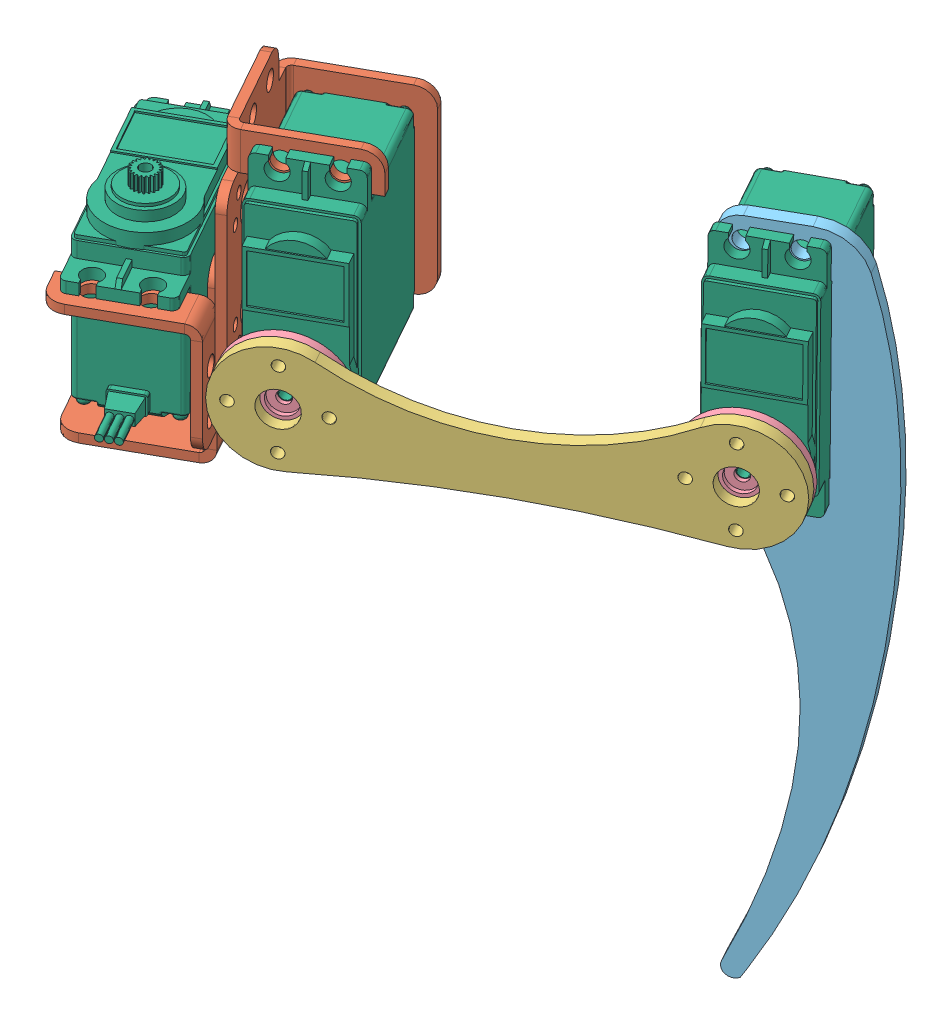
SolidWorks assembly left_leg, configuration Default. Lengths in mm.
Overall size (169.69 167.14 107.48).
10 component instances, 6 part files, 24 mates.
Components (placement in the parent):
- bearing-1: bearing [Default] at (77.3096 14.4854 59.4755) x (1 0 0) z (0 0 -1) size (9.5 4 9.5)
- coxa-1: coxa [Défaut] at (-9.8756 50.5854 -20.8316) x (0 -1 0) z (0.488008 0 0.872839) size (58 27 37.5)
- femur-1: femur [Default] at (-54.5147 84.2371 93.7229) x (-0.073248 -0.273612 -0.959047) z (0.868991 -0.489377 0.073248) size (45.33 66.4 77.86)
- metal horn-2: metal horn [Default] at (98.2503 39.7292 -104.3541) x (0.872817 -0.007119 -0.487995) z (-0.006214 -0.999975 0.003474) size (24 5 24)
- tibia-1: tibia [Default] at (-104.8708 38.6817 35.4135) x (-0.932842 0.242775 -0.266205) z (0.211271 -0.229899 -0.950006) size (45.21 146.32 43.03)
- coxa-2: coxa [Défaut] at (-2.1895 15.3354 -7.0844) x (-0.488008 0 -0.872839) z (0 1 0) size (58 27 37.5)
- servo-1: servo [Default] at (-23.955 42.3664 4.756) x (0.872839 0 -0.488008) z (0.488008 0 0.872839) size (19.81 42.14 58.23)
- servo-2: servo [Default] at (7.6485 50.8724 0.3396) x (0.872839 0 -0.488008) z (0 -1 0) size (19.81 42.14 58.23)
- servo-3: servo [Default] at (74.2287 50.408 -36.8856) x (0.872812 -0.007915 -0.487992) z (-0.006908 -0.999969 0.003863) size (19.81 42.14 58.23)
- metal horn-1: metal horn [Default] at (31.7415 40.2716 -67.1688) x (0.872817 -0.007119 -0.487995) z (-0.006214 -0.999975 0.003474) size (24 5 24)
Mates (geometry in assembly coordinates):
- Concentric1: concentric anti-aligned: cylinder of bracket-1 through (4.3143 40.8354 0.4498) axis (0.872839 0 -0.488008) radius 4; cylinder of bracket-2 through (0.8229 40.8354 2.4018) axis (-0.872839 0 0.488008) radius 4
- Concentric2: concentric anti-aligned: cylinder of bracket-1 through (0.8982 40.8354 -5.6601) axis (0.872839 0 -0.488008) radius 1.25; cylinder of bracket-2 through (-2.5931 40.8354 -3.7081) axis (-0.872839 0 0.488008) radius 1.25
- Coincident1: coincident anti-aligned: plane of bracket-1 through (-9.8756 30.0854 -20.8316) normal (-0.872839 0 0.488008); plane of bracket-2 through (-12.1936 15.3354 -24.9776) normal (0.872839 0 -0.488008)
- Coincident2: coincident anti-aligned: plane of bracket-2 through (-2.1895 48.3354 -7.0844) normal (0 1 0); plane of hs-422_sws-1 through (-6.6623 48.3354 -4.9124) normal (0 -1 0)
- Parallel2: parallel anti-aligned: plane of bracket-2 through (-13.9393 15.3354 -24.0016) normal (-0.872839 0 0.488008); plane of hs-422_sws-1 through (-6.6623 42.3664 -4.9124) normal (0.872839 0 -0.488008)
- Concentric7: concentric aligned: cylinder of hs-422_sws-1 through (-10.2885 54.0905 8.9007) axis (0 1 0) radius 1.27; cylinder of bracket-2 through (-10.2885 17.3354 8.9007) axis (0 1 0) radius 1.25
- Concentric16: concentric aligned: cylinder of ball bearing-1 through (-10.2885 11.3354 8.9007) axis (0 1 0) radius 1.5; cylinder of bracket-2 through (-10.2885 17.3354 8.9007) axis (0 1 0) radius 1.25
- Coincident12: coincident anti-aligned: plane of ball bearing-1 through (-7.1235 15.3354 8.9007) normal (0 1 0); plane of bracket-2 through (-35.7603 15.3354 -11.8014) normal (0 -1 0)
- Parallel3: parallel anti-aligned: plane of bracket-1 through (-8.1299 30.0854 -21.8076) normal (0.872839 0 -0.488008); plane of hs-422_sws-2 through (7.6485 50.8724 0.3396) normal (-0.872839 0 0.488008)
- Coincident4: coincident anti-aligned: plane of bracket-1 through (6.2287 50.5854 7.9721) normal (0.488008 0 0.872839); plane of hs-422_sws-2 through (27.8541 50.8724 -4.1188) normal (-0.488008 0 -0.872839)
- Concentric8: concentric aligned: cylinder of bracket-1 through (4.0796 40.5854 -26.3426) axis (0.488008 0 0.872839) radius 1.25; cylinder of hs-422_sws-2 through (22.0163 40.5854 5.7387) axis (0.488008 0 0.872839) radius 1.27
- Coincident6: coincident anti-aligned: plane of tibia-1 through (102.836 2.0131 -46.0414) normal (0.488008 0 0.872839); plane of hs-422_sws-3 through (94.4338 50.2512 -41.3437) normal (-0.488008 0 -0.872839)
- Concentric9: concentric anti-aligned: cylinder of tibia-1 through (88.9217 74.0376 -41.6989) axis (-0.488008 0 -0.872839) radius 1.905; cylinder of hs-422_sws-3 through (77.3705 74.0376 -62.359) axis (0.488008 0 0.872839) radius 2.1844
- Parallel4: parallel anti-aligned: plane of tibia-1 through (78.1303 29.9944 -70.4095) normal (-0.872812 0.007915 0.487992); plane of hs-422_sws-3 through (91.5209 50.2512 -46.5537) normal (0.872812 -0.007915 -0.487992)
- Coincident9: coincident anti-aligned: plane of femur-1 through (77.55 72.8061 -12.517) normal (-0.488008 0 -0.872839); plane of metal horn-2 through (93.9746 40.0429 -21.7) normal (0.488008 0 0.872839)
- Concentric12: concentric anti-aligned: cylinder of femur-1 through (93.9745 40.0429 -21.7) axis (0.488008 0 0.872839) radius 3.8735; cylinder of metal horn-2 through (94.2186 40.0429 -21.2636) axis (-0.488008 0 -0.872839) radius 1.4
- Concentric13: concentric anti-aligned: cylinder of femur-1 through (101.3935 39.9824 -25.848) axis (0.488008 0 0.872839) radius 1.2192; cylinder of metal horn-2 through (100.4175 39.9824 -27.5937) axis (-0.488008 0 -0.872839) radius 0.889
- Coincident8: coincident anti-aligned: plane of femur-1 through (77.55 72.8061 -12.517) normal (-0.488008 0 -0.872839); plane of metal horn-1 through (27.4657 40.5854 15.4853) normal (0.488008 0 0.872839)
- Concentric10: concentric anti-aligned: cylinder of femur-1 through (27.4658 40.5854 15.4853) axis (0.488008 0 0.872839) radius 3.8735; cylinder of metal horn-1 through (27.7097 40.5854 15.9217) axis (-0.488008 0 -0.872839) radius 1.4
- Concentric11: concentric anti-aligned: cylinder of femur-1 through (20.0468 40.6459 19.6333) axis (0.488008 0 0.872839) radius 1.2192; cylinder of metal horn-1 through (19.0707 40.6459 17.8876) axis (-0.488008 0 -0.872839) radius 0.889
- Concentric15: concentric anti-aligned: cylinder of hs-422_sws-3 through (88.5252 40.0429 -31.4467) axis (0.488008 0 0.872839) radius 1.27; cylinder of metal horn-2 through (94.2186 40.0429 -21.2636) axis (-0.488008 0 -0.872839) radius 1.4
- Coincident11: coincident anti-aligned: plane of hs-422_sws-3 through (101.9597 50.2512 -27.8831) normal (0.488008 0 0.872839); plane of metal horn-2 through (95.861 40.0215 -24.4733) normal (-0.488008 0 -0.872839)
- Concentric14: concentric anti-aligned: cylinder of metal horn-1 through (27.7097 40.5854 15.9217) axis (-0.488008 0 -0.872839) radius 1.4; cylinder of hs-422_sws-2 through (22.0163 40.5854 5.7387) axis (0.488008 0 0.872839) radius 1.27
- Coincident10: coincident anti-aligned: plane of metal horn-1 through (29.3521 40.564 12.7121) normal (-0.488008 0 -0.872839); plane of hs-422_sws-2 through (35.38 50.8724 9.3418) normal (0.488008 0 0.872839)
